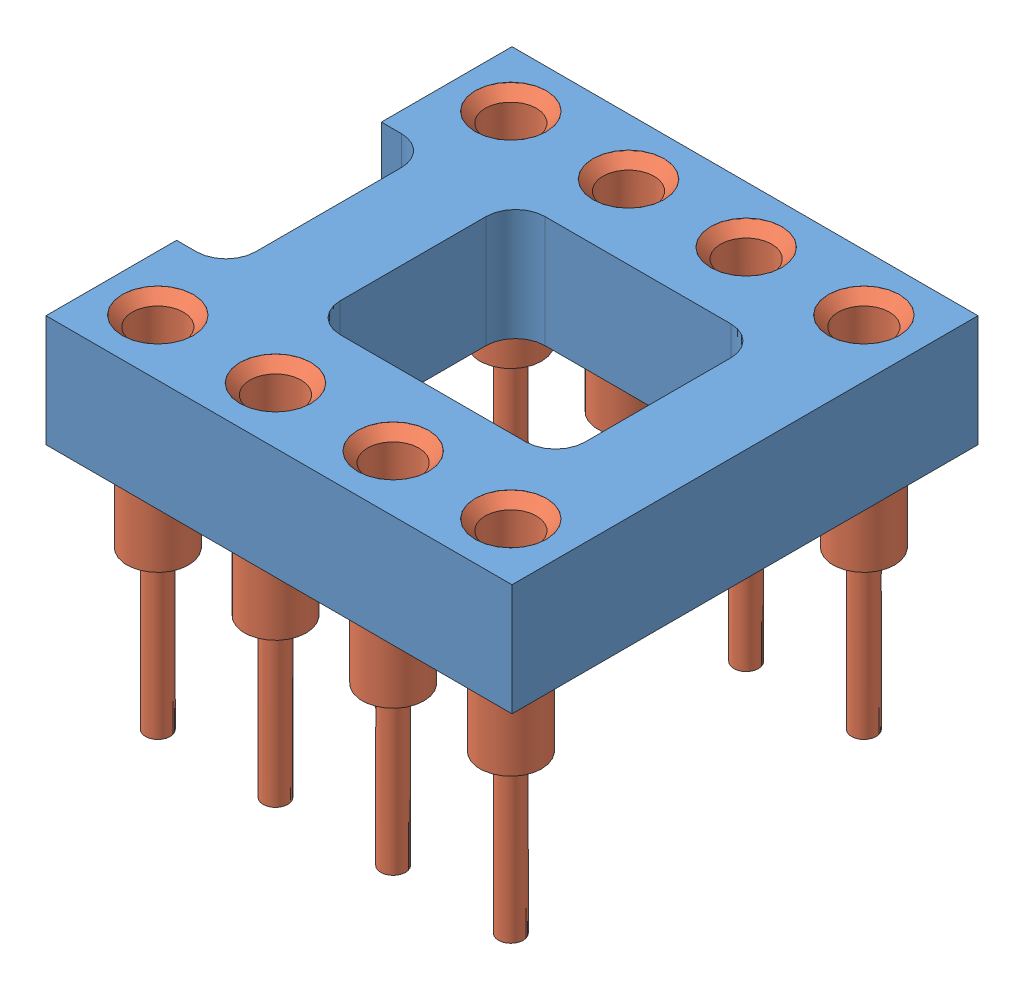
SolidWorks assembly TYCO 808-AG11D-LF, configuration Default. Lengths in mm.
Overall size (10.06 7.75 10.06).
9 component instances, 2 part files, 16 mates.
Components (placement in the parent):
- TYCO 808-AG11D-LF_1-1: TYCO 808-AG11D-LF_1 [Default] at (-0.2704 -0.4912 0.4764) size (10.06 2.41 10.06)
- TYCO 808-AG11D-LF_2-2: TYCO 808-AG11D-LF_2 [Default] at (-0.2704 0.7153 6.8899) x (1 0 0) z (0 1 0) size (1.54 1.54 7.75)
- TYCO 808-AG11D-LF_2-4: TYCO 808-AG11D-LF_2 [Default] at (-2.8104 0.7153 6.8899) x (1 0 0) z (0 1 0) size (1.54 1.54 7.75)
- TYCO 808-AG11D-LF_2-6: TYCO 808-AG11D-LF_2 [Default] at (-5.3504 0.7153 6.8899) x (1 0 0) z (0 1 0) size (1.54 1.54 7.75)
- TYCO 808-AG11D-LF_2-8: TYCO 808-AG11D-LF_2 [Default] at (-7.8904 0.7153 6.8899) x (1 0 0) z (0 1 0) size (1.54 1.54 7.75)
- TYCO 808-AG11D-LF_2-10: TYCO 808-AG11D-LF_2 [Default] at (-0.2704 0.7153 -0.7301) x (1 0 0) z (0 1 0) size (1.54 1.54 7.75)
- TYCO 808-AG11D-LF_2-12: TYCO 808-AG11D-LF_2 [Default] at (-2.8104 0.7153 -0.7301) x (1 0 0) z (0 1 0) size (1.54 1.54 7.75)
- TYCO 808-AG11D-LF_2-16: TYCO 808-AG11D-LF_2 [Default] at (-5.3504 0.7153 -0.7301) x (1 0 0) z (0 1 0) size (1.54 1.54 7.75)
- TYCO 808-AG11D-LF_2-18: TYCO 808-AG11D-LF_2 [Default] at (-7.8904 0.7153 -0.7301) x (1 0 0) z (0 1 0) size (1.54 1.54 7.75)
Mates (geometry in assembly coordinates):
- Concentric2: concentric aligned: cylinder of TYCO 808-AG11D-LF_1-1 through (3.5142 0.7153 3.0799) axis (0 -1 0) radius 0.6648; cylinder of TYCO 808-AG11D-LF_2-2 through (3.5142 14.3483 3.0799) axis (0 -1 0) radius 0.6648
- Coincident2: coincident aligned: plane of TYCO 808-AG11D-LF_1-1 through (-5.5008 0.7153 4.5003) normal (0 1 0); circle of TYCO 808-AG11D-LF_2-2
- Concentric3: concentric aligned: cylinder of TYCO 808-AG11D-LF_1-1 through (0.9742 0.7153 3.0799) axis (0 -1 0) radius 0.6648; cylinder of TYCO 808-AG11D-LF_2-4 through (0.9742 14.3483 3.0799) axis (0 -1 0) radius 0.6648
- Coincident3: coincident aligned: plane of TYCO 808-AG11D-LF_1-1 through (-5.5008 0.7153 4.5003) normal (0 1 0); circle of TYCO 808-AG11D-LF_2-4
- Concentric4: concentric aligned: cylinder of TYCO 808-AG11D-LF_1-1 through (-1.5658 0.7153 3.0799) axis (0 -1 0) radius 0.6648; cylinder of TYCO 808-AG11D-LF_2-6 through (-1.5658 14.3483 3.0799) axis (0 -1 0) radius 0.6648
- Coincident4: coincident aligned: plane of TYCO 808-AG11D-LF_1-1 through (-5.5008 0.7153 4.5003) normal (0 1 0); circle of TYCO 808-AG11D-LF_2-6
- Concentric5: concentric aligned: cylinder of TYCO 808-AG11D-LF_1-1 through (-4.1058 0.7153 3.0799) axis (0 -1 0) radius 0.6648; cylinder of TYCO 808-AG11D-LF_2-8 through (-4.1058 14.3483 3.0799) axis (0 -1 0) radius 0.6648
- Coincident5: coincident aligned: plane of TYCO 808-AG11D-LF_1-1 through (-5.5008 0.7153 4.5003) normal (0 1 0); circle of TYCO 808-AG11D-LF_2-8
- Concentric6: concentric aligned: cylinder of TYCO 808-AG11D-LF_1-1 through (3.5142 0.7153 -4.5401) axis (0 -1 0) radius 0.6648; cylinder of TYCO 808-AG11D-LF_2-10 through (3.5142 14.3483 -4.5401) axis (0 -1 0) radius 0.6648
- Coincident6: coincident aligned: plane of TYCO 808-AG11D-LF_1-1 through (-5.5008 0.7153 4.5003) normal (0 1 0); circle of TYCO 808-AG11D-LF_2-10
- Concentric7: concentric aligned: cylinder of TYCO 808-AG11D-LF_1-1 through (0.9742 0.7153 -4.5401) axis (0 -1 0) radius 0.6648; cylinder of TYCO 808-AG11D-LF_2-12 through (0.9742 14.3483 -4.5401) axis (0 -1 0) radius 0.6648
- Coincident7: coincident aligned: plane of TYCO 808-AG11D-LF_1-1 through (-5.5008 0.7153 4.5003) normal (0 1 0); circle of TYCO 808-AG11D-LF_2-12
- Concentric9: concentric aligned: cylinder of TYCO 808-AG11D-LF_1-1 through (-1.5658 0.7153 -4.5401) axis (0 -1 0) radius 0.6648; cylinder of TYCO 808-AG11D-LF_2-16 through (-1.5658 14.3483 -4.5401) axis (0 -1 0) radius 0.6648
- Coincident8: coincident aligned: plane of TYCO 808-AG11D-LF_1-1 through (-5.5008 0.7153 4.5003) normal (0 1 0); circle of TYCO 808-AG11D-LF_2-16
- Concentric10: concentric aligned: cylinder of TYCO 808-AG11D-LF_1-1 through (-4.1058 0.7153 -4.5401) axis (0 -1 0) radius 0.6648; cylinder of TYCO 808-AG11D-LF_2-18 through (-4.1058 14.3483 -4.5401) axis (0 -1 0) radius 0.6648
- Coincident9: coincident aligned: plane of TYCO 808-AG11D-LF_1-1 through (-5.5008 0.7153 4.5003) normal (0 1 0); circle of TYCO 808-AG11D-LF_2-18
